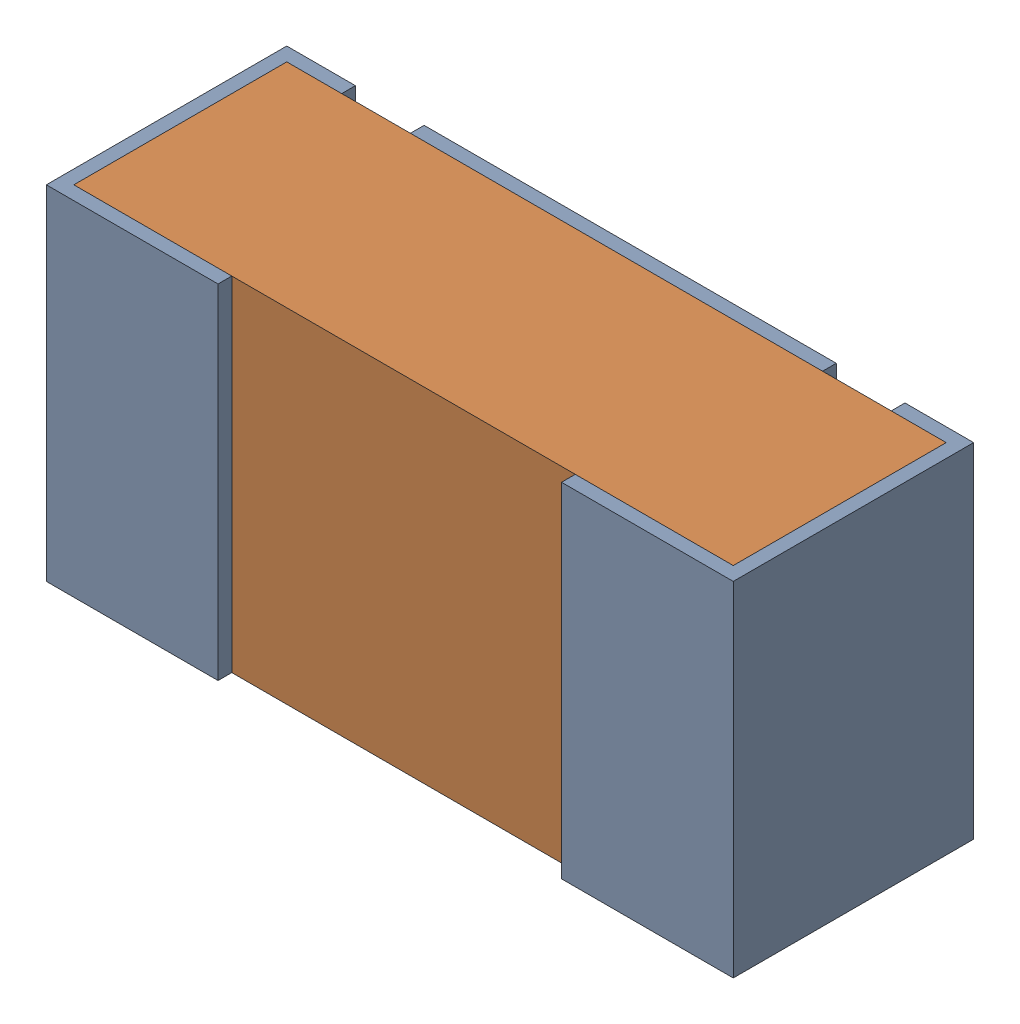
SolidWorks assembly R14, configuration Default. Lengths in mm.
Overall size (1 0.5 0.35).
3 component instances, 2 part files, 0 mates.
Components (placement in the parent):
- R14-subassembly-1-1: R14-subassembly-1 [Default] at (-1.4251 -5.7499 -1.6307) x (1 0 0) z (0 1 0) size (1 0.35 0.5)
  - 0402 resistor-1: 0402 resistor [Default] at origin size (1 0.35 0.5)
  - 0402 resistor-1-1: 0402 resistor-1 [Default] at origin size (0.96 0.31 0.5)
